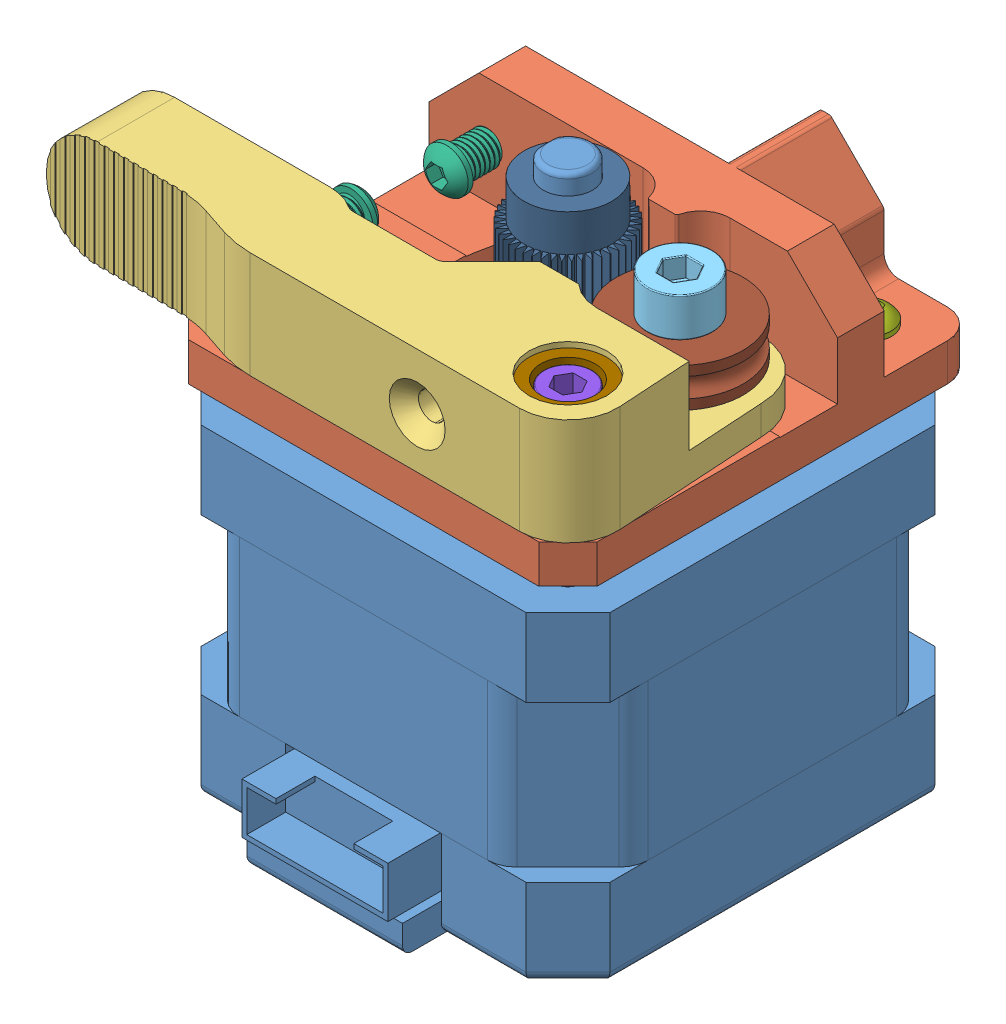
SolidWorks assembly Extruder, configuration Default. Lengths in mm.
Overall size (55.68 55.32 47.08).
13 component instances, 11 part files, 0 mates.
Components (placement in the parent):
- Nema_17-1: Nema_17 [Default] at origin size (42 55.32 47)
- Extruder_plate-1: Extruder_plate [Default] at (0 11 0) size (42 14.9 42.08)
- Extruder_arm-1: Extruder_arm [Default] at (21.46 15 21.1) size (55.68 11.19 26.8)
- M3x12-1: M3x12 [Default] at (-15.5 12.6 15.5) size (5.5 13.6 5.5)
- M4x7-1: M4x7 [Default] at (12 22 0.5) size (6.7 11 6.7)
- M3x8-1: M3x8 [Default] at (-15 19.75 -3) x (1 0 0) z (0 -1 0) size (4.5 9.55 4.5)
- M3x8-2: M3x8 [Default] at (-15.3 20.49 7) x (1 0 0) z (0 1 0) size (4.5 9.55 4.5)
- M3x14-1: M3x14 [Default] at (-15.5 14.85 -15.5) size (4.5 15.55 4.5)
- M3x14-2: M3x14 [Default] at (15.5 14.85 -15.5) size (4.5 15.55 4.5)
- M3x18-1: M3x18 [Default] at (15.5 22 15.5) size (5 21 5)
- Extruder_socket-1: Extruder_socket [Default] at (15.5 15 15.5) size (7.95 10.4 7.95)
- MK8_drive_gear-1: MK8_drive_gear [Default] at (0 28 0) x (1 0 0) z (0 -1 0) size (10.78 10.77 11)
- Idler-1: Idler [Default] at (12 18 0.5) x (1 0 0) z (0 1 0) size (13 13 4)
